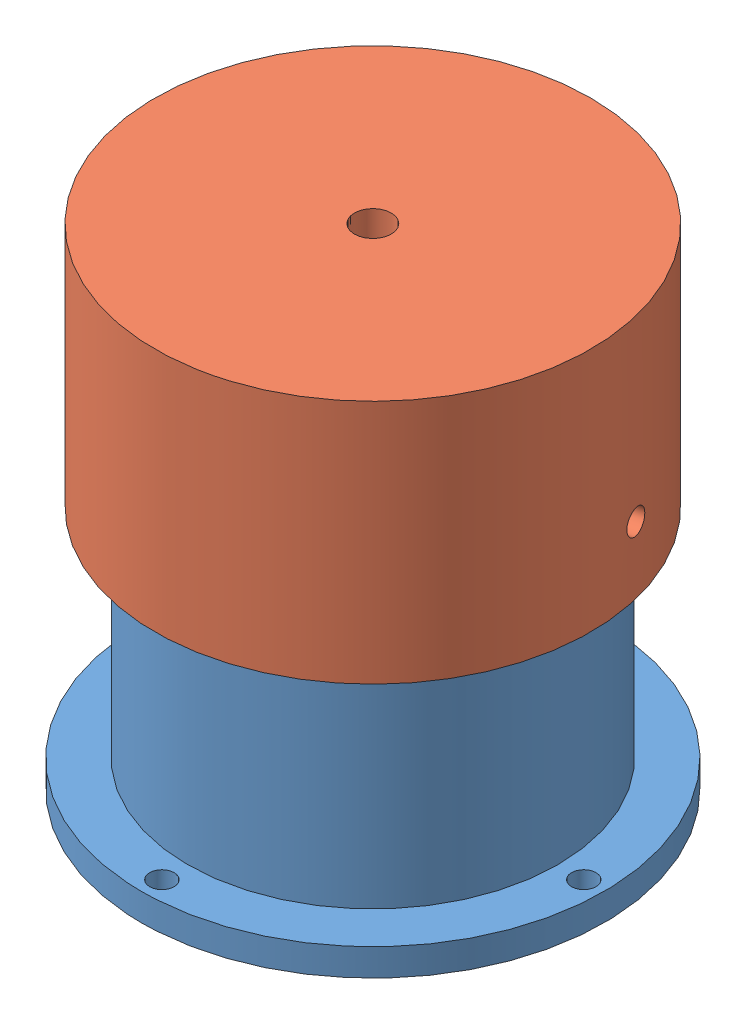
SolidWorks assembly Assemblage1, configuration Défaut. Lengths in mm.
Overall size (96.67 90 96.67).
2 component instances, 2 part files, 2 mates.
Components (placement in the parent):
- SupportCamera_Base_V1-1: SupportCamera_Base_V1 [Défaut] at (-66.3336 -31.0344 85) size (85 75 85)
- SupportCamera_Haut_V1-1: SupportCamera_Haut_V1 [Défaut] at (-66.3336 43.9656 85) x (0.97155 0 -0.236833) z (0.236833 0 0.97155) size (80 45 80)
Mates (geometry in assembly coordinates):
- Coaxiale1: concentric: circle of SupportCamera_Base_V1-1; circle of SupportCamera_Haut_V1-1
- Coïncidente2: coincident: plane of SupportCamera_Base_V1-1 through (-66.3336 43.9656 85) normal (0 1 0); plane of SupportCamera_Haut_V1-1 through (-66.3336 43.9656 85) normal (0 -1 0)
